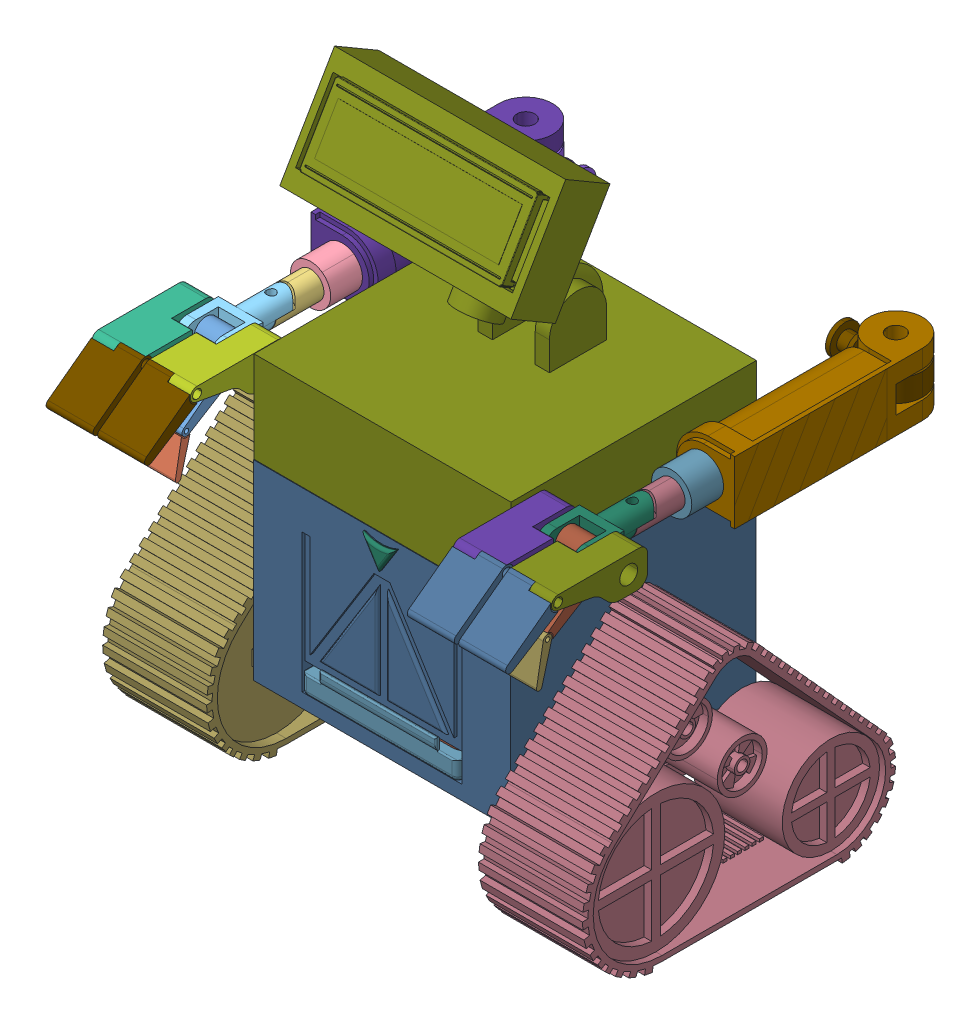
SolidWorks assembly Full Body, configuration Default. Lengths in mm.
Overall size (168.14 212.39 162.86).
196 component instances, 72 part files, 15 mates.
Components (placement in the parent):
- Clock PCB.step-1: Clock PCB.step [Default] at (-3.837 -6.133 58.5856) size (81.95 80 25.5)
  - Board.step-1: Board.step [Default] at origin size (80 80 0.41)
    - Open CASCADE STEP translator 6.8 1.1.1.step-1: Open CASCADE STEP translator 6.8 1.1.1.step [Default] at (0 0 -0.4115) size (80 80 0.41)
  - XTAL1.step-1: XTAL1.step [Default] at origin size (11.36 4.66 3.61)
    - 6606830048.step-1: 6606830048.step [Default] at (28.0499 41.0499 0) size (11.36 4.66 1.01)
      - Extruded.step-1: Extruded.step [Default] at origin size (11.36 4.66 1.01)
    - 6606829968.step-1: 6606829968.step [Default] at (28.0499 41.0501 1) size (10.05 3.71 2.61)
      - Extruded-0.step-1: Extruded-0.step [Default] at origin size (10.05 3.71 2.61)
  - U2.step-1: U2.step [Default] at origin size (10.5 4.7 16.2)
    - 6606829888.step-1: 6606829888.step [Default] at (7.95 27.55 13.05) size (10.4 1.3 6.65)
      - Extruded-1.step-1: Extruded-1.step [Default] at origin size (10.4 1.3 6.65)
    - 6606829728.step-1: 6606829728.step [Default] at (7.95 25.9 3.5) size (10.5 4.7 9.55)
      - Extruded-2.step-1: Extruded-2.step [Default] at origin size (10.5 4.7 9.55)
  - U1.step-1: U1.step [Default] at origin size (63.7 16.03 14.45)
    - User_Library-ZIF-Socket-28-pin.step-1: User_Library-ZIF-Socket-28-pin.step [Default] at (43.5 28.05 0) x (1 0 0) z (0 0 1) size (63.7 16.03 14.45)
      - Contacts.step-1: Contacts.step [Default] at origin size (34.37 11.24 1.5)
      - Pins001.step-1: Pins001.step [Default] at origin size (33.87 8.47 3)
      - Screw002.step-1: Screw002.step [Default] at origin size (2.8 2.8 2)
      - Bottom-Shape.step-1: Bottom-Shape.step [Default] at origin size (50.4 15.02 8.11)
      - Lever-Tip.step-1: Lever-Tip.step [Default] at origin size (7 4.8 4.8)
      - Top-Shape.step-1: Top-Shape.step [Default] at origin size (50.4 15.02 3.8)
      - Push-Bar.step-1: Push-Bar.step [Default] at origin size (3.85 15.02 3.7)
      - Lever-Bar.step-1: Lever-Bar.step [Default] at origin size (19.2 11.43 1.62)
      - Screw001.step-1: Screw001.step [Default] at origin size (2.8 2.8 2)
  - Q1.step-1: Q1.step [Default] at origin size (3.05 4.08 12.8)
    - BC547-B.step-1: BC547-B.step [Default] at (72 53.1536 7) x (0 1 0) z (0 0 -1) size (4.08 3.05 12.8)
  - P3.step-1: P3.step [Default] at origin size (2.54 10.16 11.54)
    - 61300411121.step-1: 61300411121.step [Default] at (76.2999 22.6001 1.3) x (0 1 0) z (1 0 0) size (10.16 11.54 2.54)
      - 6130xx11121_PIN.step-1: 6130xx11121_PIN.step [Default] at (-3.81 1.5 0) x (1 0 0) z (0 -1 0) size (0.64 0.64 11.54)
      - 6130xx11121_PIN.step-2: 6130xx11121_PIN.step [Default] at (-1.27 1.5 0) x (1 0 0) z (0 -1 0) size (0.64 0.64 11.54)
      - 6130xx11121_PIN.step-3: 6130xx11121_PIN.step [Default] at (1.27 1.5 0) x (1 0 0) z (0 -1 0) size (0.64 0.64 11.54)
      - 6130xx11121_PIN.step-4: 6130xx11121_PIN.step [Default] at (3.81 1.5 0) x (1 0 0) z (0 -1 0) size (0.64 0.64 11.54)
      - 61300411121-3.step-1: 61300411121-3.step [Default] at origin size (10.16 2.54 2.54)
  - P2.step-1: P2.step [Default] at origin size (17.78 2.54 11.54)
    - 61300711121.step-1: 61300711121.step [Default] at (39.9599 3.8999 1.3) x (-1 0 0) z (0 1 0) size (17.78 11.54 2.54)
      - 6130xx11121_PIN-4.step-1: 6130xx11121_PIN-4.step [Default] at (-7.62 1.5 0) x (1 0 0) z (0 -1 0) size (0.64 0.64 11.54)
      - 6130xx11121_PIN-4.step-2: 6130xx11121_PIN-4.step [Default] at (-5.08 1.5 0) x (1 0 0) z (0 -1 0) size (0.64 0.64 11.54)
      - 6130xx11121_PIN-4.step-3: 6130xx11121_PIN-4.step [Default] at (-2.54 1.5 0) x (1 0 0) z (0 -1 0) size (0.64 0.64 11.54)
      - 6130xx11121_PIN-4.step-4: 6130xx11121_PIN-4.step [Default] at (0 1.5 0) x (1 0 0) z (0 -1 0) size (0.64 0.64 11.54)
      - 6130xx11121_PIN-4.step-5: 6130xx11121_PIN-4.step [Default] at (2.54 1.5 0) x (1 0 0) z (0 -1 0) size (0.64 0.64 11.54)
      - 6130xx11121_PIN-4.step-6: 6130xx11121_PIN-4.step [Default] at (5.08 1.5 0) x (1 0 0) z (0 -1 0) size (0.64 0.64 11.54)
      - 6130xx11121_PIN-4.step-7: 6130xx11121_PIN-4.step [Default] at (7.62 1.5 0) x (1 0 0) z (0 -1 0) size (0.64 0.64 11.54)
      - 61300711121-5.step-1: 61300711121-5.step [Default] at origin size (17.78 2.54 2.54)
  - P1.step-1: P1.step [Default] at origin size (30.48 2.54 11.54)
    - 61301211121.step-1: 61301211121.step [Default] at (41.3799 75.6999 1.3) x (-1 0 0) z (0 1 0) size (30.48 11.54 2.54)
      - 6130xx11121_PIN-6.step-1: 6130xx11121_PIN-6.step [Default] at (-13.97 1.5 0) x (1 0 0) z (0 -1 0) size (0.64 0.64 11.54)
      - 6130xx11121_PIN-6.step-2: 6130xx11121_PIN-6.step [Default] at (-11.43 1.5 0) x (1 0 0) z (0 -1 0) size (0.64 0.64 11.54)
      - 6130xx11121_PIN-6.step-3: 6130xx11121_PIN-6.step [Default] at (-8.89 1.5 0) x (1 0 0) z (0 -1 0) size (0.64 0.64 11.54)
      - 6130xx11121_PIN-6.step-4: 6130xx11121_PIN-6.step [Default] at (-6.35 1.5 0) x (1 0 0) z (0 -1 0) size (0.64 0.64 11.54)
      - 6130xx11121_PIN-6.step-5: 6130xx11121_PIN-6.step [Default] at (-3.81 1.5 0) x (1 0 0) z (0 -1 0) size (0.64 0.64 11.54)
      - 6130xx11121_PIN-6.step-6: 6130xx11121_PIN-6.step [Default] at (-1.27 1.5 0) x (1 0 0) z (0 -1 0) size (0.64 0.64 11.54)
      - 6130xx11121_PIN-6.step-7: 6130xx11121_PIN-6.step [Default] at (1.27 1.5 0) x (1 0 0) z (0 -1 0) size (0.64 0.64 11.54)
      - 6130xx11121_PIN-6.step-8: 6130xx11121_PIN-6.step [Default] at (3.81 1.5 0) x (1 0 0) z (0 -1 0) size (0.64 0.64 11.54)
      - 6130xx11121_PIN-6.step-9: 6130xx11121_PIN-6.step [Default] at (6.35 1.5 0) x (1 0 0) z (0 -1 0) size (0.64 0.64 11.54)
      - 6130xx11121_PIN-6.step-10: 6130xx11121_PIN-6.step [Default] at (8.89 1.5 0) x (1 0 0) z (0 -1 0) size (0.64 0.64 11.54)
      - 6130xx11121_PIN-6.step-11: 6130xx11121_PIN-6.step [Default] at (11.43 1.5 0) x (1 0 0) z (0 -1 0) size (0.64 0.64 11.54)
      - 6130xx11121_PIN-6.step-12: 6130xx11121_PIN-6.step [Default] at (13.97 1.5 0) x (1 0 0) z (0 -1 0) size (0.64 0.64 11.54)
      - 61301211121-7.step-1: 61301211121-7.step [Default] at origin size (30.48 2.54 2.54)
  - KEY5.step-1: KEY5.step [Default] at origin size (7.8 5.99 8.11)
    - Switch_TE_1825910-2_eec.step-1: Switch_TE_1825910-2_eec.step [Default] at (68.1 13.85 0) size (7.8 5.99 8.11)
      - Body.step-1: Body.step [Default] at (0 0 4.3) x (0 -1 0) z (0 0 1) size (5.99 5.99 3.9)
      - button.step-1: button.step [Default] at (0 0 4.3) x (0 -1 0) z (0 0 1) size (3.51 3.51 1.1)
      - cover.step-1: cover.step [Default] at (0 0 4.3) x (0 -1 0) z (0 0 1) size (5.99 5.99 0.1)
      - leads.step-1: leads.step [Default] at (0 0 4.3) x (0 -1 0) z (0 0 1) size (5.21 7.8 4.81)
      - circle.step-1: circle.step [Default] at (-2.6803 2.6863 3.6) size (0.4 0.4 0)
      - TE_Connectivity.step-1: TE_Connectivity.step [Default] at (-0.1925 -2.4218 3.6) size (2.27 0.85 0.01)
  - KEY4.step-1: KEY4.step [Default] at origin size (7.8 5.99 8.11)
    - Switch_TE_1825910-2_eec.step-1: Switch_TE_1825910-2_eec.step [Default] at (50 55 0) size (7.8 5.99 8.11)
      - Body.step-1: Body.step [Default] at (0 0 4.3) x (0 -1 0) z (0 0 1) size (5.99 5.99 3.9)
      - button.step-1: button.step [Default] at (0 0 4.3) x (0 -1 0) z (0 0 1) size (3.51 3.51 1.1)
      - cover.step-1: cover.step [Default] at (0 0 4.3) x (0 -1 0) z (0 0 1) size (5.99 5.99 0.1)
      - leads.step-1: leads.step [Default] at (0 0 4.3) x (0 -1 0) z (0 0 1) size (5.21 7.8 4.81)
      - circle.step-1: circle.step [Default] at (-2.6803 2.6863 3.6) size (0.4 0.4 0)
      - TE_Connectivity.step-1: TE_Connectivity.step [Default] at (-0.1925 -2.4218 3.6) size (2.27 0.85 0.01)
  - KEY3.step-1: KEY3.step [Default] at origin size (7.8 5.99 8.11)
    - Switch_TE_1825910-2_eec.step-1: Switch_TE_1825910-2_eec.step [Default] at (30 55 0) size (7.8 5.99 8.11)
      - Body.step-1: Body.step [Default] at (0 0 4.3) x (0 -1 0) z (0 0 1) size (5.99 5.99 3.9)
      - button.step-1: button.step [Default] at (0 0 4.3) x (0 -1 0) z (0 0 1) size (3.51 3.51 1.1)
      - cover.step-1: cover.step [Default] at (0 0 4.3) x (0 -1 0) z (0 0 1) size (5.99 5.99 0.1)
      - leads.step-1: leads.step [Default] at (0 0 4.3) x (0 -1 0) z (0 0 1) size (5.21 7.8 4.81)
      - circle.step-1: circle.step [Default] at (-2.6803 2.6863 3.6) size (0.4 0.4 0)
      - TE_Connectivity.step-1: TE_Connectivity.step [Default] at (-0.1925 -2.4218 3.6) size (2.27 0.85 0.01)
  - KEY2.step-1: KEY2.step [Default] at origin size (7.8 5.99 8.11)
    - Switch_TE_1825910-2_eec.step-1: Switch_TE_1825910-2_eec.step [Default] at (40 45 0) size (7.8 5.99 8.11)
      - Body.step-1: Body.step [Default] at (0 0 4.3) x (0 -1 0) z (0 0 1) size (5.99 5.99 3.9)
      - button.step-1: button.step [Default] at (0 0 4.3) x (0 -1 0) z (0 0 1) size (3.51 3.51 1.1)
      - cover.step-1: cover.step [Default] at (0 0 4.3) x (0 -1 0) z (0 0 1) size (5.99 5.99 0.1)
      - leads.step-1: leads.step [Default] at (0 0 4.3) x (0 -1 0) z (0 0 1) size (5.21 7.8 4.81)
      - circle.step-1: circle.step [Default] at (-2.6803 2.6863 3.6) size (0.4 0.4 0)
      - TE_Connectivity.step-1: TE_Connectivity.step [Default] at (-0.1925 -2.4218 3.6) size (2.27 0.85 0.01)
  - KEY1.step-1: KEY1.step [Default] at origin size (7.8 5.99 8.11)
    - Switch_TE_1825910-2_eec.step-1: Switch_TE_1825910-2_eec.step [Default] at (40 65 0) size (7.8 5.99 8.11)
      - Body.step-1: Body.step [Default] at (0 0 4.3) x (0 -1 0) z (0 0 1) size (5.99 5.99 3.9)
      - button.step-1: button.step [Default] at (0 0 4.3) x (0 -1 0) z (0 0 1) size (3.51 3.51 1.1)
      - cover.step-1: cover.step [Default] at (0 0 4.3) x (0 -1 0) z (0 0 1) size (5.99 5.99 0.1)
      - leads.step-1: leads.step [Default] at (0 0 4.3) x (0 -1 0) z (0 0 1) size (5.21 7.8 4.81)
      - circle.step-1: circle.step [Default] at (-2.6803 2.6863 3.6) size (0.4 0.4 0)
      - TE_Connectivity.step-1: TE_Connectivity.step [Default] at (-0.1925 -2.4218 3.6) size (2.27 0.85 0.01)
  - JST2.step-1: JST2.step [Default] at origin size (4.7 6 10.05)
    - Conn_TE_Connectivity_440054-2_eec.step-1: Conn_TE_Connectivity_440054-2_eec.step [Default] at (72.85 68.85 0) x (0 -1 0) z (0 0 1) size (6 4.7 10.05)
      - 1.step-1: 1.step [Default] at (0 -0.6 6.05) size (2.5 2.35 8.8)
      - 2.step-1: 2.step [Default] at (0 -0.6 6.05) size (0.9 0.1 1.08)
      - 3.step-1: 3.step [Default] at (0 -0.6 6.05) size (6 4.7 6.35)
      - TE_connectivity_Logo_1_(2).step-1: TE_connectivity_Logo_1_(2).step [Default] at (2.901 6.9182 0.6322) x (0 -1 0) z (1 0 0) size (1.49 0.53 0.1)
  - JST1.step-1: JST1.step [Default] at origin size (6 4.7 10.05)
    - Conn_TE_Connectivity_440054-2_eec.step-1: Conn_TE_Connectivity_440054-2_eec.step [Default] at (10.55 4.25 0) x (-1 0 0) z (0 0 1) size (6 4.7 10.05)
      - 1.step-1: 1.step [Default] at (0 -0.6 6.05) size (2.5 2.35 8.8)
      - 2.step-1: 2.step [Default] at (0 -0.6 6.05) size (0.9 0.1 1.08)
      - 3.step-1: 3.step [Default] at (0 -0.6 6.05) size (6 4.7 6.35)
      - TE_connectivity_Logo_1_(2).step-1: TE_connectivity_Logo_1_(2).step [Default] at (2.901 6.9182 0.6322) x (0 -1 0) z (1 0 0) size (1.49 0.53 0.1)
  - JST3.step-1: JST3.step [Default] at origin size (7.9 4.5 9.4)
    - 6606829248.step-1: 6606829248.step [Default] at (11.9 70.55 -3.4) size (0.5 0.5 8.45)
      - Extruded-8.step-1: Extruded-8.step [Default] at origin size (0.5 0.5 8.45)
    - 6606829248.step-2: 6606829248.step [Default] at (7.9 70.55 -3.4) size (0.5 0.5 8.45)
      - Extruded-8.step-1: Extruded-8.step [Default] at origin size (0.5 0.5 8.45)
    - 6606829248.step-3: 6606829248.step [Default] at (9.9 70.55 -3.4) size (0.5 0.5 8.45)
      - Extruded-8.step-1: Extruded-8.step [Default] at origin size (0.5 0.5 8.45)
    - 6606828928.step-1: 6606828928.step [Default] at (9.9 70.2 0) size (6.6 4.1 1.75)
      - Extruded-9.step-1: Extruded-9.step [Default] at origin size (6.6 4.1 1.75)
    - 6606828768.step-1: 6606828768.step [Default] at (9.9 68.875 0) size (7.9 2.25 6)
      - Extruded-10.step-1: Extruded-10.step [Default] at origin size (7.9 2.25 6)
    - 6606828608.step-1: 6606828608.step [Default] at (7.525 71.525 0) size (3.15 1.45 6)
      - Extruded-11.step-1: Extruded-11.step [Default] at origin size (3.15 1.45 6)
    - 6606828448.step-1: 6606828448.step [Default] at (6.275 70.4 0) size (0.65 0.8 4.1)
      - Extruded-12.step-1: Extruded-12.step [Default] at origin size (0.65 0.8 4.1)
    - 6606828448.step-2: 6606828448.step [Default] at (13.525 70.4 0) size (0.65 0.8 4.1)
      - Extruded-12.step-1: Extruded-12.step [Default] at origin size (0.65 0.8 4.1)
    - 6606828208.step-1: 6606828208.step [Default] at (12.275 71.525 0) size (3.15 1.45 6)
      - Extruded-13.step-1: Extruded-13.step [Default] at origin size (3.15 1.45 6)
  - C6.step-1: C6.step [Default] at origin size (8 8 14.5)
    - Aluminum_electrolytic_capacitor_radial_D8_H11.5_PinD0.6_Pitch3.5_nominal_black.step-1: Aluminum_electrolytic_capacitor_radial_D8_H11.5_PinD0.6_Pitch3.5_nominal_black.step [Default] at (64.35 73.55 0) x (-1 0 0) z (0 0 1) size (1.1 2.07 11.1)
    - Aluminum_electrolytic_capacitor_radial_D8_H11.5_PinD0.6_Pitch3.5_nominal_black-14.step-1: Aluminum_electrolytic_capacitor_radial_D8_H11.5_PinD0.6_Pitch3.5_nominal_black-14.step [Default] at (64.35 73.55 0) x (-1 0 0) z (0 0 1) size (7.86 8 11.1)
    - Aluminum_electrolytic_capacitor_radial_D8_H11.5_PinD0.6_Pitch3.5_nominal_black-15.step-1: Aluminum_electrolytic_capacitor_radial_D8_H11.5_PinD0.6_Pitch3.5_nominal_black-15.step [Default] at (64.35 73.55 0) x (-1 0 0) z (0 0 1) size (7.8 7.8 10.9)
    - Aluminum_electrolytic_capacitor_radial_D8_H11.5_PinD0.6_Pitch3.5_nominal_black-16.step-1: Aluminum_electrolytic_capacitor_radial_D8_H11.5_PinD0.6_Pitch3.5_nominal_black-16.step [Default] at (64.35 73.55 0) x (-1 0 0) z (0 0 1) size (7.4 7.4 1.6)
    - Aluminum_electrolytic_capacitor_radial_D8_H11.5_PinD0.6_Pitch3.5_nominal_black-17.step-1: Aluminum_electrolytic_capacitor_radial_D8_H11.5_PinD0.6_Pitch3.5_nominal_black-17.step [Default] at (64.35 73.55 0) x (-1 0 0) z (0 0 1) size (4.1 0.6 3)
  - C5.step-1: C5.step [Default] at origin size (8 8 14.5)
    - Aluminum_electrolytic_capacitor_radial_D8_H11.5_PinD0.6_Pitch3.5_nominal_black.step-1: Aluminum_electrolytic_capacitor_radial_D8_H11.5_PinD0.6_Pitch3.5_nominal_black.step [Default] at (65.05 5.25 0) size (1.1 2.07 11.1)
    - Aluminum_electrolytic_capacitor_radial_D8_H11.5_PinD0.6_Pitch3.5_nominal_black-14.step-1: Aluminum_electrolytic_capacitor_radial_D8_H11.5_PinD0.6_Pitch3.5_nominal_black-14.step [Default] at (65.05 5.25 0) size (7.86 8 11.1)
    - Aluminum_electrolytic_capacitor_radial_D8_H11.5_PinD0.6_Pitch3.5_nominal_black-15.step-1: Aluminum_electrolytic_capacitor_radial_D8_H11.5_PinD0.6_Pitch3.5_nominal_black-15.step [Default] at (65.05 5.25 0) size (7.8 7.8 10.9)
    - Aluminum_electrolytic_capacitor_radial_D8_H11.5_PinD0.6_Pitch3.5_nominal_black-16.step-1: Aluminum_electrolytic_capacitor_radial_D8_H11.5_PinD0.6_Pitch3.5_nominal_black-16.step [Default] at (65.05 5.25 0) size (7.4 7.4 1.6)
    - Aluminum_electrolytic_capacitor_radial_D8_H11.5_PinD0.6_Pitch3.5_nominal_black-17.step-1: Aluminum_electrolytic_capacitor_radial_D8_H11.5_PinD0.6_Pitch3.5_nominal_black-17.step [Default] at (65.05 5.25 0) size (4.1 0.6 3)
  - C4.step-1: C4.step [Default] at origin size (5.99 5.99 8.89)
    - Cap_Murata_RCE5C2A3R0C0K1H03B_eec.step-1: Cap_Murata_RCE5C2A3R0C0K1H03B_eec.step [Default] at (13.7 39.4 0) x (1 0 0) z (0 0 1) size (5.99 5.99 8.89)
      - Body.step-1: Body.step [Default] at origin size (5.99 5.99 3.9)
      - leads-18.step-1: leads-18.step [Default] at origin size (5.5 0.5 6.65)
      - logo.step-1: logo.step [Default] at (0 -1.25 8.5) x (1 0 0) z (0 -1 0) size (1.98 0.46 0.01)
  - C3.step-1: C3.step [Default] at origin size (5.99 5.99 8.89)
    - Cap_Murata_RCE5C2A3R0C0K1H03B_eec.step-1: Cap_Murata_RCE5C2A3R0C0K1H03B_eec.step [Default] at (13.65 43.7 0) x (1 0 0) z (0 0 1) size (5.99 5.99 8.89)
      - Body.step-1: Body.step [Default] at origin size (5.99 5.99 3.9)
      - leads-18.step-1: leads-18.step [Default] at origin size (5.5 0.5 6.65)
      - logo.step-1: logo.step [Default] at (0 -1.25 8.5) x (1 0 0) z (0 -1 0) size (1.98 0.46 0.01)
  - C2.step-1: C2.step [Default] at origin size (8 8 14.5)
    - Aluminum_electrolytic_capacitor_radial_D8_H11.5_PinD0.6_Pitch3.5_nominal_black.step-1: Aluminum_electrolytic_capacitor_radial_D8_H11.5_PinD0.6_Pitch3.5_nominal_black.step [Default] at (17.55 14.1 0) size (1.1 2.07 11.1)
    - Aluminum_electrolytic_capacitor_radial_D8_H11.5_PinD0.6_Pitch3.5_nominal_black-14.step-1: Aluminum_electrolytic_capacitor_radial_D8_H11.5_PinD0.6_Pitch3.5_nominal_black-14.step [Default] at (17.55 14.1 0) size (7.86 8 11.1)
    - Aluminum_electrolytic_capacitor_radial_D8_H11.5_PinD0.6_Pitch3.5_nominal_black-15.step-1: Aluminum_electrolytic_capacitor_radial_D8_H11.5_PinD0.6_Pitch3.5_nominal_black-15.step [Default] at (17.55 14.1 0) size (7.8 7.8 10.9)
    - Aluminum_electrolytic_capacitor_radial_D8_H11.5_PinD0.6_Pitch3.5_nominal_black-16.step-1: Aluminum_electrolytic_capacitor_radial_D8_H11.5_PinD0.6_Pitch3.5_nominal_black-16.step [Default] at (17.55 14.1 0) size (7.4 7.4 1.6)
    - Aluminum_electrolytic_capacitor_radial_D8_H11.5_PinD0.6_Pitch3.5_nominal_black-17.step-1: Aluminum_electrolytic_capacitor_radial_D8_H11.5_PinD0.6_Pitch3.5_nominal_black-17.step [Default] at (17.55 14.1 0) size (4.1 0.6 3)
  - C1.step-1: C1.step [Default] at origin size (8 8 14.5)
    - Aluminum_electrolytic_capacitor_radial_D8_H11.5_PinD0.6_Pitch3.5_nominal_black.step-1: Aluminum_electrolytic_capacitor_radial_D8_H11.5_PinD0.6_Pitch3.5_nominal_black.step [Default] at (7.05 14.5 0) size (1.1 2.07 11.1)
    - Aluminum_electrolytic_capacitor_radial_D8_H11.5_PinD0.6_Pitch3.5_nominal_black-14.step-1: Aluminum_electrolytic_capacitor_radial_D8_H11.5_PinD0.6_Pitch3.5_nominal_black-14.step [Default] at (7.05 14.5 0) size (7.86 8 11.1)
    - Aluminum_electrolytic_capacitor_radial_D8_H11.5_PinD0.6_Pitch3.5_nominal_black-15.step-1: Aluminum_electrolytic_capacitor_radial_D8_H11.5_PinD0.6_Pitch3.5_nominal_black-15.step [Default] at (7.05 14.5 0) size (7.8 7.8 10.9)
    - Aluminum_electrolytic_capacitor_radial_D8_H11.5_PinD0.6_Pitch3.5_nominal_black-16.step-1: Aluminum_electrolytic_capacitor_radial_D8_H11.5_PinD0.6_Pitch3.5_nominal_black-16.step [Default] at (7.05 14.5 0) size (7.4 7.4 1.6)
    - Aluminum_electrolytic_capacitor_radial_D8_H11.5_PinD0.6_Pitch3.5_nominal_black-17.step-1: Aluminum_electrolytic_capacitor_radial_D8_H11.5_PinD0.6_Pitch3.5_nominal_black-17.step [Default] at (7.05 14.5 0) size (4.1 0.6 3)
  - Free-Models.step-1: Free-Models.step [Default] at origin size (34.6 9.68 7.3)
    - atmega328p-pu.step-1: atmega328p-pu.step [Default] at (59.217 28 11) x (-1 0 0) z (0 1 0) size (34.6 7.3 9.68)
- Part46^Full Body-1: Part46^Full Body [Default] at origin size (90 95.83 86) (virtual)
- Matrix Keypad 12 Key (4X3)-3: Matrix Keypad 12 Key (4X3) [Default] at (36.3513 -10.233 60.678) x (1 0 0) z (0 1 0) size (54 77 1.31)
- wheel 2-2: wheel 2 [Default] at (-18.6112 -22.8736 33.5298) size (56.04 84.58 109.67)
- Mirrorwheel 2-5: Mirrorwheel 2 [Default] at (91.0372 -22.8736 33.5298) x (-1 0 0) z (0 0 -1) size (56.04 84.58 109.67)
- Part4^Full Body-1: Part4^Full Body [Default] at (36.3513 -10.233 60.678) x (-1 0 0) z (0 -1 0) size (55 82.09 11) (virtual)
- Part5^Full Body-1: Part5^Full Body [Default] at (0 0 101.5856) size (12.45 10.37 39.83) (virtual)
- upper part-1: upper part [Default] at (71.8557 119.3769 -12.5727) x (-1 0 0) z (0 0 1) size (90 115.82 86)
- Right Side Arm.STEP-1: Right Side Arm.STEP [Default] at (-27.5484 69.6953 52.2262) x (0 0 1) z (1 0 0) size (162.86 40.32 34.94)
  - Arm - Main Body.STEP-1: Arm - Main Body.STEP [Default] at (0 0.0454 0.4989) size (75.28 21.96 21.96)
  - Hand Part 2.STEP-1: Hand Part 2.STEP [Default] at (76.5707 1.9044 -16.7528) x (0 0 -1) z (-0.824824 -0.56539 0) size (16.47 4.7 24.32)
  - Hand Part 3.STEP-1: Hand Part 3.STEP [Default] at (48.6366 3.2369 -7.3421) x (0 0 -1) z (-0.852186 -0.523239 0) size (15.68 8.63 29.87)
  - Hand Part 4.STEP-1: Hand Part 4.STEP [Default] at (63.8343 21.1945 8.3398) x (0 0 1) z (-0.217332 -0.976098 0) size (15.68 3.13 16.03)
  - Hydraulic Arm.STEP-1: Hydraulic Arm.STEP [Default] at (30.1041 0.0454 0.4989) x (1 0 0) z (0 -1 0) size (58.03 9.41 9.41)
  - Hydraulic Cylinder.STEP-1: Hydraulic Cylinder.STEP [Default] at (-14.7434 0.0454 0.4989) x (1 0 0) z (0 -0.817741 0.575587) size (51.75 14.11 14.11)
  - Wrist.STEP-1: Wrist.STEP [Default] at (51.2775 0.0441 0.4989) size (31.37 9.42 15.68)
  - Hand Part 1.STEP-1: Hand Part 1.STEP [Default] at (43.4365 0.0441 -0.286) x (0 0 1) z (1 0 0) size (16.47 12.55 33.72)
  - Hand Part 1-2.STEP-1: Hand Part 1-2.STEP [Default] at (43.4365 0.0441 17.7505) x (0 0 1) z (1 0 0) size (16.47 12.55 33.72)
  - Hand Part 2.STEP-2: Hand Part 2.STEP [Default] at (76.5707 1.9044 17.7505) x (0 0 1) z (-0.824824 -0.56539 0) size (16.47 4.7 24.32)
  - Sholder.STEP-1: Sholder.STEP [Default] at (-65.8673 0.0454 -1.0683) x (0 0 -1) z (0 1 0) size (28.67 18.82 10.83)
- MirrorRight Side Arm.STEP-2: MirrorRight Side Arm.STEP [Default] at (99.9745 69.6953 52.2262) x (0 0 1) z (1 0 0) size (162.86 40.32 34.94)
  - MirrorArm - Main Body.STEP-1: MirrorArm - Main Body.STEP [Default] at (0 0.0454 -0.4989) size (75.28 21.96 21.96)
  - MirrorHand Part 2.STEP-1: MirrorHand Part 2.STEP [Default] at (76.5707 1.9044 16.7528) x (0 0 1) z (0.824824 0.56539 0) size (16.47 4.7 24.32)
  - MirrorHand Part 3.STEP-1: MirrorHand Part 3.STEP [Default] at (48.6366 3.2369 7.3421) x (0 0 1) z (0.852186 0.523239 0) size (15.68 8.63 29.87)
  - MirrorHand Part 4.STEP-1: MirrorHand Part 4.STEP [Default] at (63.8343 21.1945 -8.3398) x (0 0 -1) z (0.217332 0.976098 0) size (15.68 3.13 16.03)
  - MirrorHydraulic Arm.STEP-1: MirrorHydraulic Arm.STEP [Default] at (30.1041 0.0454 -0.4989) x (1 0 0) z (0 1 0) size (58.03 9.41 9.41)
  - MirrorHydraulic Cylinder.STEP-1: MirrorHydraulic Cylinder.STEP [Default] at (-14.7434 0.0454 -0.4989) x (1 0 0) z (0 0.817741 0.575587) size (51.75 14.11 14.11)
  - MirrorWrist.STEP-1: MirrorWrist.STEP [Default] at (51.2775 0.0441 -0.4989) size (31.37 9.42 15.68)
  - MirrorHand Part 1.STEP-1: MirrorHand Part 1.STEP [Default] at (43.4365 0.0441 0.286) x (0 0 -1) z (-1 0 0) size (16.47 12.55 33.72)
  - MirrorHand Part 1-2.STEP-1: MirrorHand Part 1-2.STEP [Default] at (43.4365 0.0441 -17.7505) x (0 0 -1) z (-1 0 0) size (16.47 12.55 33.72)
  - MirrorHand Part 2.STEP-2: MirrorHand Part 2.STEP [Default] at (76.5707 1.9044 -17.7505) x (0 0 -1) z (0.824824 0.56539 0) size (16.47 4.7 24.32)
  - MirrorSholder.STEP-1: MirrorSholder.STEP [Default] at (-65.8673 0.0454 1.0683) x (0 0 1) z (0 -1 0) size (28.67 18.82 10.83)
Mates (geometry in assembly coordinates):
- Perpendicular1: perpendicular: plane of Part46^Lower Body-1 through (-8.787 -22.233 101.5856) normal (0 -1 0); plane of wheel 2-2 through (-10.3877 -22.301 50.7401) normal (0 0 -1)
- InPlace1: in place: plane of ? through (70.3473 -28.3571 185.2121) normal (0 -1 0); plane of ? through (0 -28.3571 0) normal (0 -1 0); moOrthogonalPlaneRef_w of ? through (70.3473 -28.3571 185.2121) normal (0 -1 0); plane of ? through (0 -28.3571 0) normal (0 0 -1); plane of ? through (70.3473 -28.3571 185.2121) normal (0 -1 0); plane of ? through (0 -28.3571 0) normal (-1 0 0); plane of Matrix Keypad 12 Key (4X3)-3 through (36.3513 -10.233 60.678) normal (0 -1 0); unknown of Part4^Full Body-1
- Coincident8: coincident aligned: plane of ?; plane of ?
- Coincident9: coincident aligned: moOrthogonalPlaneRef_w of Matrix Keypad 12 Key (4X3)-3 through (36.3513 -10.233 60.678) normal (0 0 -1); plane of Part4^Initial-1 through (36.3513 -10.233 60.678) normal (0 0 -1)
- Coincident10: coincident anti-aligned: moOrthogonalPlaneRef_w of Matrix Keypad 12 Key (4X3)-3 through (36.3513 -10.233 60.678) normal (1 0 0); plane of Part4^Initial-1 through (36.3513 -10.233 60.678) normal (-1 0 0)
- Parallel2: parallel anti-aligned: plane of Part46^Lower Body-1 through (8.213 -6.233 21.5856) normal (1 0 0); plane of Part4^Initial-1 through (8.8513 -17.233 102.635) normal (-1 0 0)
- Parallel3: parallel anti-aligned: plane of Part46^Lower Body-1 through (64.213 -6.233 21.5856) normal (-1 0 0); plane of Part4^Initial-1 through (63.8513 -17.233 102.635) normal (1 0 0)
- Distance1: distance = 0 mm anti-aligned: plane of Part4^Initial-1 through (36.3513 -17.233 60.678) normal (0 -1 0); plane of Part46^Lower Body-1 through (6.213 -17.233 21.5856) normal (0 1 0)
- InPlace2: in place: plane of Part46^Full Body-1 through (0 0 101.5856) normal (0 0 1); plane of Part5^Full Body-1 through (0 0 101.5856) normal (0 0 1); plane of Part46^Full Body-1 through (0 0 101.5856) normal (0 0 1); plane of Part5^Full Body-1 through (0 0 101.5856) normal (0 1 0); plane of Part46^Full Body-1 through (0 0 101.5856) normal (0 0 1); plane of Part5^Full Body-1 through (0 0 101.5856) normal (1 0 0); plane of Part46^Full Body-1 through (0 0 101.5856) normal (0 0 1); unknown of Part5^Full Body-1
- Coincident14: coincident aligned: plane of ?; plane of ?
- Coincident15: coincident aligned: moOrthogonalPlaneRef_w of Part46^Lower Body-1 through (0 0 101.5856) normal (0 1 0); plane of Part5^Initial-1 through (0 0 101.5856) normal (0 1 0)
- Coincident16: coincident anti-aligned: moOrthogonalPlaneRef_w of Part46^Lower Body-1 through (0 0 101.5856) normal (-1 0 0); plane of Part5^Initial-1 through (0 0 101.5856) normal (1 0 0)
- Coincident1: coincident anti-aligned: plane of Part46^Lower Body-1 through (-8.787 44.767 101.5856) normal (0 1 0); plane of upper part-1 through (36.195 44.767 58.3799) normal (0 -1 0)
- Lock4: lock: unknown of Part46^Lower Body-1; unknown of upper part-1
- Lock5: lock: unknown of Part46^Lower Body-1; unknown of wheel 2-2
